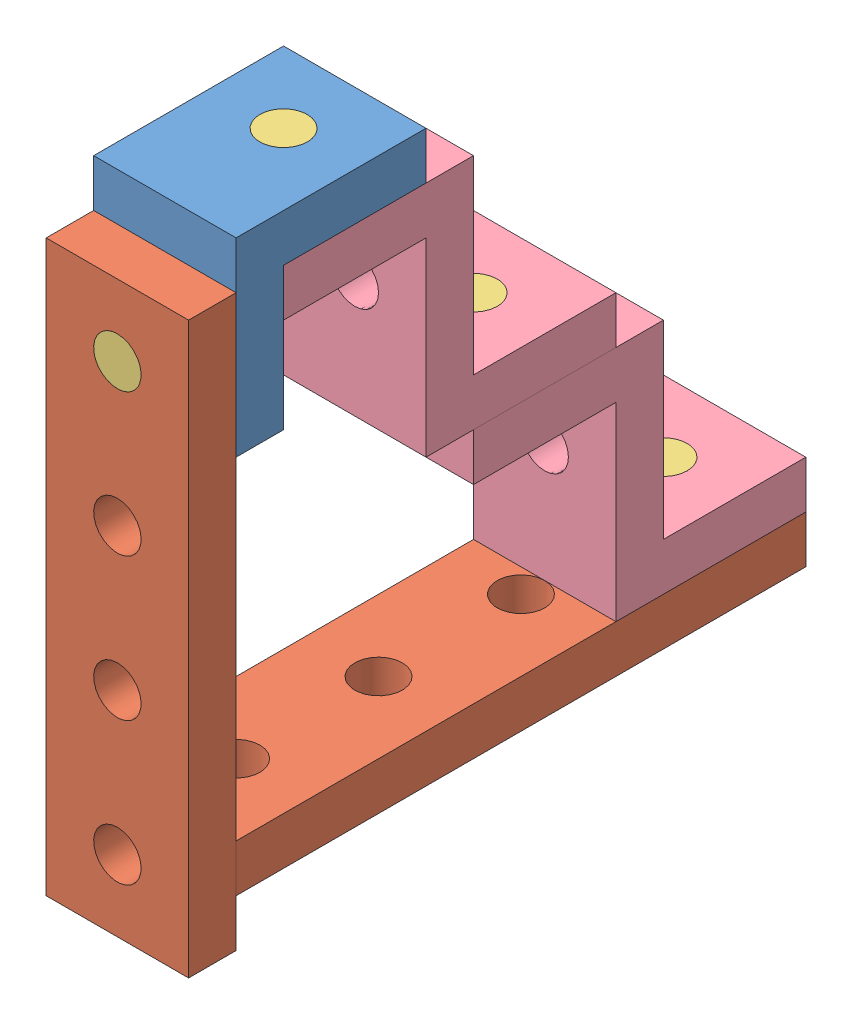
SolidWorks assembly Assem1, configuration Default. Lengths in mm.
Overall size (30 130 130).
9 component instances, 4 part files, 21 mates.
Components (placement in the parent):
- L-Bracket-1: L-Bracket [Default] at (-30 130 -10) x (1 0 0) z (0 1 0) size (30 40 40)
- Plate, Quad-1: Plate, Quad [Default] at (0 120 0) x (0 -1 0) z (0 0 -1) size (120 30 10)
- PG20-1-1: PG20-1 [Default] at (-15 105 -20) x (0.834324 0.551275 0) z (0 0 1) size (10 10 20)
- Z-Bracket-1: Z-Bracket [Default] at (0 70 -90) x (-1 0 0) z (0 0 -1) size (30 50 70)
- Z-Bracket-2: Z-Bracket [Default] at (0 70 -60) x (-1 0 0) z (0 0 1) size (30 50 70)
- Plate, Quad-2: Plate, Quad [Default] at (-30 10 -130) x (0 0 1) z (0 1 0) size (120 30 10)
- PG20-1-2: PG20-1 [Default] at (-15 110 -35) x (0.142667 0 -0.989771) z (0 1 0) size (10 10 20)
- PG20-1-3: PG20-1 [Default] at (-15 10 -115) x (0.768418 0 -0.639948) z (0 1 0) size (10 10 20)
- PG20-1-4: PG20-1 [Default] at (-15 60 -75) x (0.261445 0 0.965218) z (0 1 0) size (10 10 20)
Mates (geometry in assembly coordinates):
- Coincident29: coincident: point of Plate, Quad-1
- Parallel1: parallel aligned: plane of Plate, Quad-1 through (0 120 -10) normal (0 1 0)
- Coincident31: coincident aligned: plane of Plate, Quad-1 through (0 120 -10) normal (1 0 0)
- Concentric2: concentric anti-aligned: cylinder of Plate, Quad-1 through (-15 105 -10) axis (0 0 1) radius 5; cylinder of PG20-1-1 through (-15 105 0) axis (0 0 -1) radius 5
- Coincident32: coincident anti-aligned: circle of Plate, Quad-1; circle of PG20-1-1
- Concentric3: concentric aligned: cylinder of L-Bracket-1 through (-15 105 10) axis (0 0 -1) radius 5; cylinder of PG20-1-1 through (-15 105 0) axis (0 0 -1) radius 5
- Coincident33: coincident aligned: plane of L-Bracket-1 through (0 130 -10) normal (1 0 0); plane of Plate, Quad-1 through (0 120 -10) normal (1 0 0)
- Concentric4: concentric aligned: cylinder of L-Bracket-1 through (-15 150 -35) axis (0 -1 0) radius 5; cylinder of PG20-1-2 through (-15 130 -35) axis (0 -1 0) radius 5
- Coincident34: coincident anti-aligned: circle of L-Bracket-1; circle of PG20-1-2
- Coincident37: coincident anti-aligned: circle of L-Bracket-1; circle of PG20-1-1
- Concentric5: concentric anti-aligned: cylinder of Z-Bracket-1 through (-15 90 -35) axis (0 1 0) radius 5; cylinder of PG20-1-2 through (-15 130 -35) axis (0 -1 0) radius 5
- Coincident38: coincident anti-aligned: plane of L-Bracket-1 through (0 120 -20) normal (0 0 -1); plane of Z-Bracket-1 through (-30 110 -20) normal (0 0 1)
- Coincident39: coincident aligned: circle of Z-Bracket-1; circle of PG20-1-2
- Coincident40: coincident anti-aligned: circle of Z-Bracket-2; circle of PG20-1-4
- Concentric6: concentric aligned: cylinder of Z-Bracket-2 through (-15 90 -75) axis (0 -1 0) radius 5; cylinder of PG20-1-4 through (-15 80 -75) axis (0 -1 0) radius 5
- Coincident41: coincident aligned: plane of Z-Bracket-2 through (-30 30 -130) normal (0 0 -1); plane of Plate, Quad-2 through (-30 20 -130) normal (0 0 -1)
- Coincident42: coincident aligned: circle of Plate, Quad-2; circle of PG20-1-3
- Coincident43: coincident anti-aligned: circle of Z-Bracket-2; circle of PG20-1-3
- Concentric7: concentric anti-aligned: cylinder of Z-Bracket-1 through (-15 50 -75) axis (0 1 0) radius 5; cylinder of PG20-1-4 through (-15 80 -75) axis (0 -1 0) radius 5
- Parallel2: parallel aligned: plane of Z-Bracket-1 through (-30 80 -90) normal (0 0 -1); plane of Z-Bracket-2 through (-30 70 -100) normal (0 0 -1)
- Coincident45: coincident aligned: circle of Z-Bracket-1; circle of PG20-1-4
